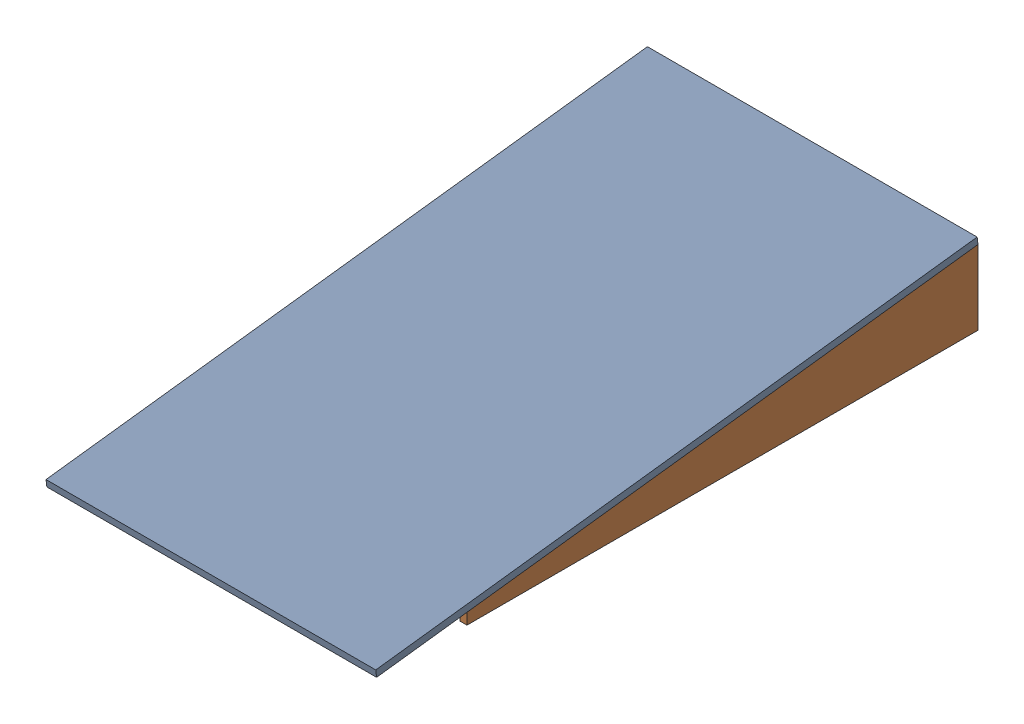
SolidWorks assembly GE-16137_ASM, configuration Default. Lengths in mm.
Overall size (606.42 149.25 1107.6).
5 component instances, 4 part files, 0 mates.
Components (placement in the parent):
- GE-16137-01-1: GE-16137-01 [Default] at origin size (606.42 149.03 1107.6)
- GE-16137-02-1: GE-16137-02 [Default] at (593.725 0 -103.7451) x (1 0 0) z (0 0.000201 1) size (12.7 136.64 939.8)
- GE-16137-02-2: GE-16137-02 [Default] at (0 0 -103.7451) x (1 0 0) z (0 0.000201 1) size (12.7 136.64 939.8)
- GE-16137-03-1: GE-16137-03 [Default] at (12.7 -0.2194 -1197.061) x (1 0 0) z (0 0.000201 1) size (581.02 134.94 12.7)
- GE-16137-04-1: GE-16137-04 [Default] at (12.7 -0.0928 -566.3226) x (1 0 0) z (0 0.000201 1) size (581.02 57.15 12.7)
